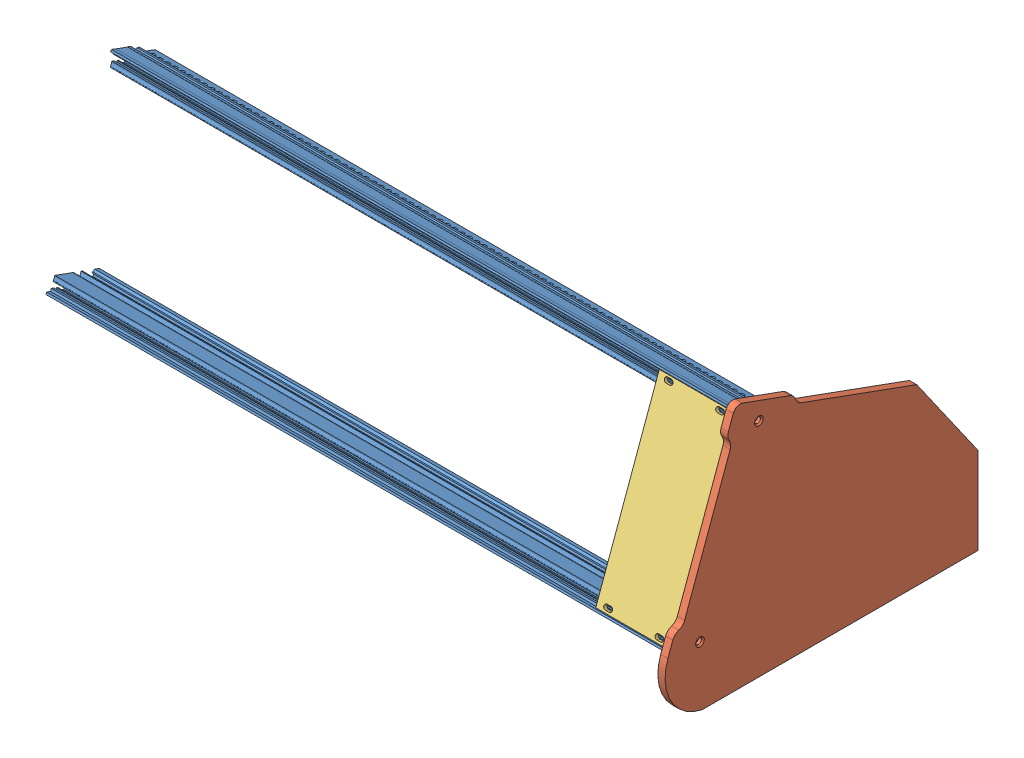
SolidWorks assembly Euro-Rack, configuration Standard. Lengths in mm.
Overall size (434.8 233.05 260.96).
4 component instances, 3 part files, 12 mates.
Components (placement in the parent):
- Trägerprofil GB 29L-1: Trägerprofil GB 29L [Standard] at (-434.8 165.0112 164.5566) x (0 -0.34202 -0.939693) z (1 0 0) size (35.6 10 431.8)
- Seitenplatte-1: Seitenplatte [Standard] at (-5 165.0112 164.5566) x (0 -0.34202 -0.939693) z (1 0 0) size (216.07 169.36 5)
- Trägerprofil GB 29L-2: Trägerprofil GB 29L [Standard] at (-3 40.7839 209.7717) x (0 -0.34202 -0.939693) z (-1 0 0) size (35.6 10 431.8)
- Frontplatte-1: Frontplatte [10TE] at (-55.5 42.3962 208.8656) x (-1 0 0) z (0 -0.34202 -0.939693) size (50.5 128.55 2.5)
Mates (geometry in assembly coordinates):
- Deckungsgleich5: coincident anti-aligned: plane of Trägerprofil GB 29L-1 through (0.0032 159.2661 151.696) normal (1 0 0); plane of Seitenplatte-1 through (0.0032 165.0112 164.5566) normal (-1 0 0)
- Deckungsgleich6: coincident aligned: plane of Trägerprofil GB 29L-1 through (0.0032 163.7426 165.0184) normal (0 0.34202 0.939693); plane of Seitenplatte-1 through (3.0032 59.5777 202.9313) normal (0 0.34202 0.939693)
- Deckungsgleich7: coincident aligned: plane of Trägerprofil GB 29L-1 through (0.0032 165.0112 164.5566) normal (0 0.939693 -0.34202); plane of Seitenplatte-1 through (3.0032 149.6203 122.2705) normal (0 0.939693 -0.34202)
- Deckungsgleich8: coincident anti-aligned: plane of Seitenplatte-1 through (0.0032 165.0112 164.5566) normal (-1 0 0); plane of Trägerprofil GB 29L-2 through (0.0032 36.9182 196.227) normal (1 0 0)
- Deckungsgleich9: coincident aligned: plane of Trägerprofil GB 29L-1 through (0.0032 163.7426 165.0184) normal (0 0.34202 0.939693); plane of Trägerprofil GB 29L-2 through (-431.7968 42.0524 209.31) normal (0 0.34202 0.939693)
- Abstand1: distance = 126.2 mm anti-aligned: plane of Trägerprofil GB 29L-2 through (-434.8 41.9612 204.2351) normal (0 0.939693 -0.34202); plane of Trägerprofil GB 29L-1 through (-3 160.5504 161.0722) normal (0 -0.939693 0.34202)
- Deckungsgleich11: coincident anti-aligned: plane of Trägerprofil GB 29L-1 through (0.0032 161.2345 162.9515) normal (0 0.34202 0.939693); plane of Frontplatte-1 through (-52.4968 41.5411 206.5164) normal (0 -0.34202 -0.939693)
- Deckungsgleich12: coincident anti-aligned: plane of Seitenplatte-1 through (-1.9968 31.4948 184.2503) normal (-1 0 0); plane of Frontplatte-1 through (-1.9968 41.5411 206.5164) normal (1 0 0)
- Breite1: width aligned: plane of Frontplatte-1 through (-52.4968 162.3386 162.5497) normal (0 0.939693 -0.34202); plane of Frontplatte-1 through (-52.4968 41.5411 206.5164) normal (0 -0.939693 0.34202); plane of Trägerprofil GB 29L-2 through (-431.7968 41.0948 206.6788) normal (0 0.939693 -0.34202); plane of Trägerprofil GB 29L-1 through (0.0032 162.785 162.3872) normal (0 -0.939693 0.34202)
- Deckungsgleich13: coincident anti-aligned: plane of Seitenplatte-1 through (3.0032 0 190.7539) normal (0 -1 0); plane of assembly through (0 0 0) normal (0 1 0)
- Deckungsgleich15: coincident anti-aligned: plane of ? through (3.0032 0 0) normal (0 0 -1)
- Deckungsgleich16: coincident aligned: plane of Seitenplatte-1 through (0 31.4948 184.2503) normal (1 0 0); plane of assembly
